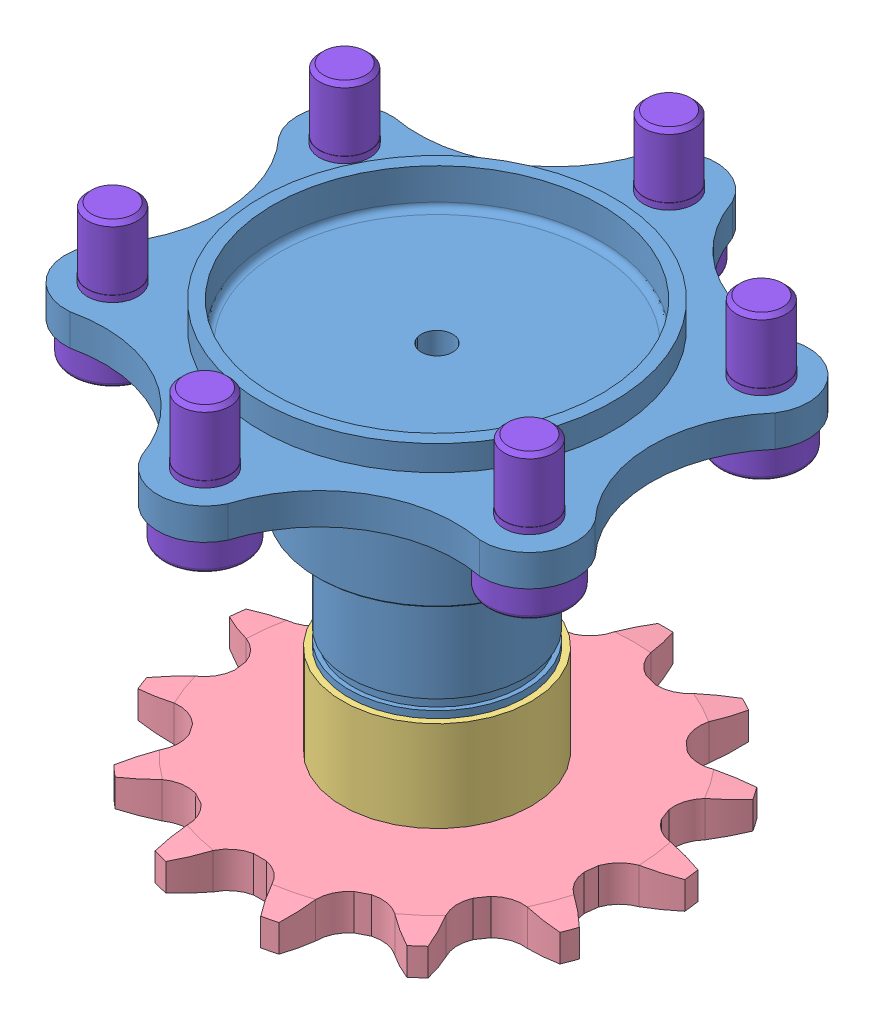
SolidWorks assembly PUTM-S-TR-GR-Adapter_Assembly, configuration Domyślna. Lengths in mm.
Overall size (117.41 90.04 113.49).
13 component instances, 8 part files, 0 mates.
Components (placement in the parent):
- PUTM-S-TR-GR_Adapter-1: PUTM-S-TR-GR_Adapter [Domyślna] at (1782 -41 258) x (0.484174 0 -0.874972) z (0 -1 0) size (79.92 89.97 74.35)
- PUTM-S-TR-GR-Bushing-1: PUTM-S-TR-GR-Bushing [Domyślna] at (1782 -111.35 258) x (-0.857183 0 0.515011) z (0 1 0) size (30 30 5.65)
- PUTM-S-TR-GR-Sprocket_Bushing-1: PUTM-S-TR-GR-Sprocket_Bushing [Domyślna] at (1782 -99.1 258) x (-1 0 0) z (0 1 0) size (30 30 14.4)
- PUTM-S-TR-GR-Sprocket_13t-1: PUTM-S-TR-GR-Sprocket_13t [Domyślna] at (1782 -99.6 258) x (1 0 0) z (0 -1 0) size (72.26 71.75 5.78)
- PUTM-S-TR-GR-Plate-1: PUTM-S-TR-GR-Plate [Domyślna] at (1782 -111.35 258) x (-0.486229 0 0.873832) z (0 -1 0) size (30 29.28 2)
- PUTM-S-TR-GR-Retainer_Plate-1: PUTM-S-TR-GR-Retainer_Plate [Domyślna] at (1782 -113.7394 258) x (-0.858002 0 0.513646) z (0 -1 0) size (20.2 21.74 7)
- PUTM-FT-FABORY_DIN933-1: PUTM-FT-FABORY_DIN933 [M8x18 [01210.080.018]] at (1782 -120.0394 258) x (0 -1 0) z (0 0 1) size (23.3 15.01 13)
- PUTM-FT-FABORY_DIN7984-1: PUTM-FT-FABORY_DIN7984 [M8x16 [07090.080.016]] at (1814.8114 -51 276.1565) x (0 -1 0) z (0.532829 0 -0.846223) size (21 13 13)
- PUTM-FT-FABORY_DIN7984-2: PUTM-FT-FABORY_DIN7984 [M8x16 [07090.080.016]] at (1749.8703 -51 277.3373) x (0 -1 0) z (-0.546944 0 0.837169) size (21 13 13)
- PUTM-FT-FABORY_DIN7984-3: PUTM-FT-FABORY_DIN7984 [M8x16 [07090.080.016]] at (1782.6817 -51 295.4938) x (0 -1 0) z (-0.541043 0 0.840995) size (21 13 13)
- PUTM-FT-FABORY_DIN7984-4: PUTM-FT-FABORY_DIN7984 [M8x16 [07090.080.016]] at (1814.1297 -51 238.6627) x (0 -1 0) z (-0.546944 0 0.837169) size (21 13 13)
- PUTM-FT-FABORY_DIN7984-5: PUTM-FT-FABORY_DIN7984 [M8x16 [07090.080.016]] at (1749.1886 -51 239.8435) x (0 -1 0) z (-0.546944 0 0.837169) size (21 13 13)
- PUTM-FT-FABORY_DIN7984-6: PUTM-FT-FABORY_DIN7984 [M8x16 [07090.080.016]] at (1781.3183 -51 220.5062) x (0 -1 0) z (-0.546944 0 0.837169) size (21 13 13)
